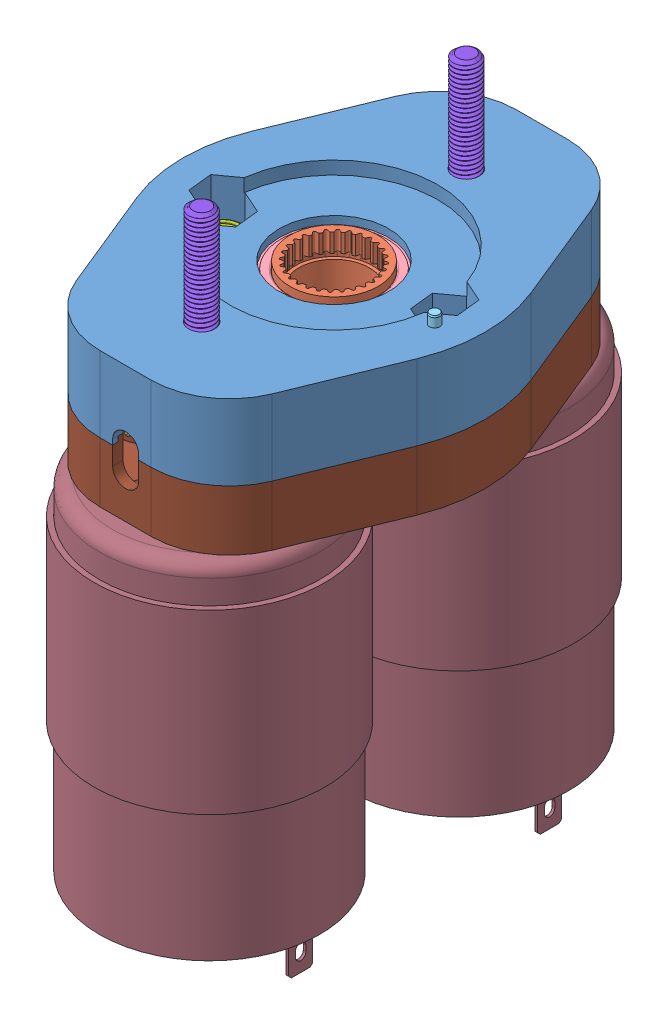
SolidWorks assembly IFI_217-3141-RS775, configuration Default. Lengths in mm.
Overall size (58 120.43 92.08).
24 component instances, 13 part files, 6 mates.
Components (placement in the parent):
- 217-3141-001 Rev1-1: 217-3141-001 Rev1 [Default] x (0 0 1) z (-1 0 0) size (80 14.5 58)
- 217-3141-007 Rev1_30T 32DP-1: 217-3141-007 Rev1_30T 32DP [Default] at (0 -7.06 0) x (0 -1 0) z (-0.999183 0 0.040426) size (22.38 25.55 25.47)
- 217-3141-006 Rev1_30T 32DP-1: 217-3141-006 Rev1_30T 32DP [Default] at (0 -9.85 -23.8887) x (-0.095925 0 -0.995389) z (0 -1 0) size (25.47 25.55 10)
- 217-3141-006 Rev1_30T 32DP-2: 217-3141-006 Rev1_30T 32DP [Default] at (0 -9.85 23.8887) x (-0.001725 0 0.999999) z (0 -1 0) size (25.47 25.55 10)
- 217-2741-1: 217-2741 [Default] at (0 2.75 0) x (0 -1 0) z (-0.999445 0 -0.033298) size (5 26 26)
- 217-2741-2: 217-2741 [Default] at (0 -13.25 0) x (0 -1 0) z (-0.537831 0 0.843053) size (5 26 26)
- PINL-M020-006-S-1: PINL-M020-006-S [Default] at (22.7445 5.75 3.4184) x (0 1 0) z (-0.890225 0 0.455522) size (6 2 2)
- SSS1032-0188-ZB-1: SSS1032-0188-ZB [Default] at (-0.3489 -11.725 -27.5094) x (-0.758755 -0.647259 0.073121) z (0.095925 0 0.995389) size (4.91 4.91 5.06)
- SSS1032-0188-ZB-2: SSS1032-0188-ZB [Default] at (-0.0063 -11.725 27.5262) x (0.762269 -0.647259 0.001315) z (0.001725 0 -0.999999) size (4.91 4.91 5.06)
- NUT-832-NYLOCK-1: NUT-832-NYLOCK [Default] at (19.244 -4.75 -2.0226) x (0.913545 0 0.406737) z (-0.406737 0 0.913545) size (10.2 4.9 8.12)
- NUT-832-NYLOCK-2: NUT-832-NYLOCK [Default] at (-19.244 -4.75 2.0226) x (0.912648 0 0.408747) z (-0.408747 0 0.912648) size (10.2 4.9 8.12)
- 91251A346_91251A346-1: 91251A346_91251A346 [Default] at (0 25.975 25.4) x (1 0 0) z (0 1 0) size (7.92 7.92 27.28)
- 91251A346_91251A346-2: 91251A346_91251A346 [Default] at (0 25.975 -25.4) x (1 0 0) z (0 1 0) size (7.92 7.92 27.28)
- SSA_SSAM4-0010ZC-1: SSA_SSAM4-0010ZC [Default] at (12.5 -17.25 -23.8887) size (7 14 7)
- SSA_SSA0832-0750ZC-1: SSA_SSA0832-0750ZC [Default] at (19.244 -19.25 -2.0226) x (-0.091926 0 -0.995766) z (-0.995766 0 0.091926) size (6.73 23.11 6.73)
- SSA_SSA0832-0750ZC-2: SSA_SSA0832-0750ZC [Default] at (-19.244 -19.25 2.0226) x (-0.18632 0 -0.982489) z (-0.982489 0 0.18632) size (6.73 23.11 6.73)
- SSA_SSAM4-0010ZC-2: SSA_SSAM4-0010ZC [Default] at (-12.5 -17.25 23.8887) x (0.677756 0 0.735287) z (-0.735287 0 0.677756) size (7 14 7)
- SSA_SSAM4-0010ZC-3: SSA_SSAM4-0010ZC [Default] at (12.5 -17.25 23.8887) x (0.994338 0 -0.106265) z (0.106265 0 0.994338) size (7 14 7)
- SSA_SSAM4-0010ZC-4: SSA_SSAM4-0010ZC [Default] at (-12.5 -17.25 -23.8887) x (0.537906 0 -0.843005) z (0.843005 0 0.537906) size (7 14 7)
- 217-3141-002 Rev2-1: 217-3141-002 Rev2 [Default] at (0 -13 0) x (0 0 1) z (0 1 0) size (80 58 12.5)
- 217-2625-011 Rev1-1: 217-2625-011 Rev1 [Default] at (0 -11.1 -23.8887) x (0.095925 0 0.995389) z (-0.995389 0 0.095925) size (8.01 7.5 7.94)
- 217-2625-011 Rev1-2: 217-2625-011 Rev1 [Default] at (0 -11 23.8887) x (-0.964857 0 0.262777) z (-0.262777 0 -0.964857) size (8.01 7.5 7.94)
- IFI_217-4347-1: IFI_217-4347 [Default] at (0 -19.25 23.8887) x (0 -1 0) z (0 0 1) size (88 44.3 44.3)
- IFI_217-4347-2: IFI_217-4347 [Default] at (0 -19.25 -23.8887) x (0 -1 0) z (0 0 1) size (88 44.3 44.3)
Mates (geometry in assembly coordinates):
- Concentric2: concentric anti-aligned: cylinder of 217-3141-002 Rev2-1 through (0 -6.75 23.8887) axis (0 -1 0) radius 6; cylinder of IFI_217-4347-1 through (0 -19.25 23.8887) axis (0 1 0) radius 8.9
- Coincident2: coincident anti-aligned: plane of 217-3141-002 Rev2-1 through (0 -19.25 0) normal (0 -1 0); plane of IFI_217-4347-1 through (8.9 -19.25 23.8887) normal (0 1 0)
- Coincident3: coincident anti-aligned: plane of 217-3141-002 Rev2-1 through (0 -19.25 0) normal (0 -1 0); plane of IFI_217-4347-2 through (8.9 -19.25 -23.8887) normal (0 1 0)
- Concentric3: concentric anti-aligned: cylinder of 217-3141-002 Rev2-1 through (0 -6.75 -23.8887) axis (0 -1 0) radius 6; cylinder of IFI_217-4347-2 through (0 -19.25 -23.8887) axis (0 1 0) radius 8.9
- Parallel1: parallel aligned: plane of IFI_217-4347-1 through (0 -19.25 23.8887) normal (0 0 1); plane of assembly through (0 0 0) normal (0 0 1)
- Parallel2: parallel aligned: plane of IFI_217-4347-2 through (0 -19.25 -23.8887) normal (0 0 1); plane of assembly through (0 0 0) normal (0 0 1)
